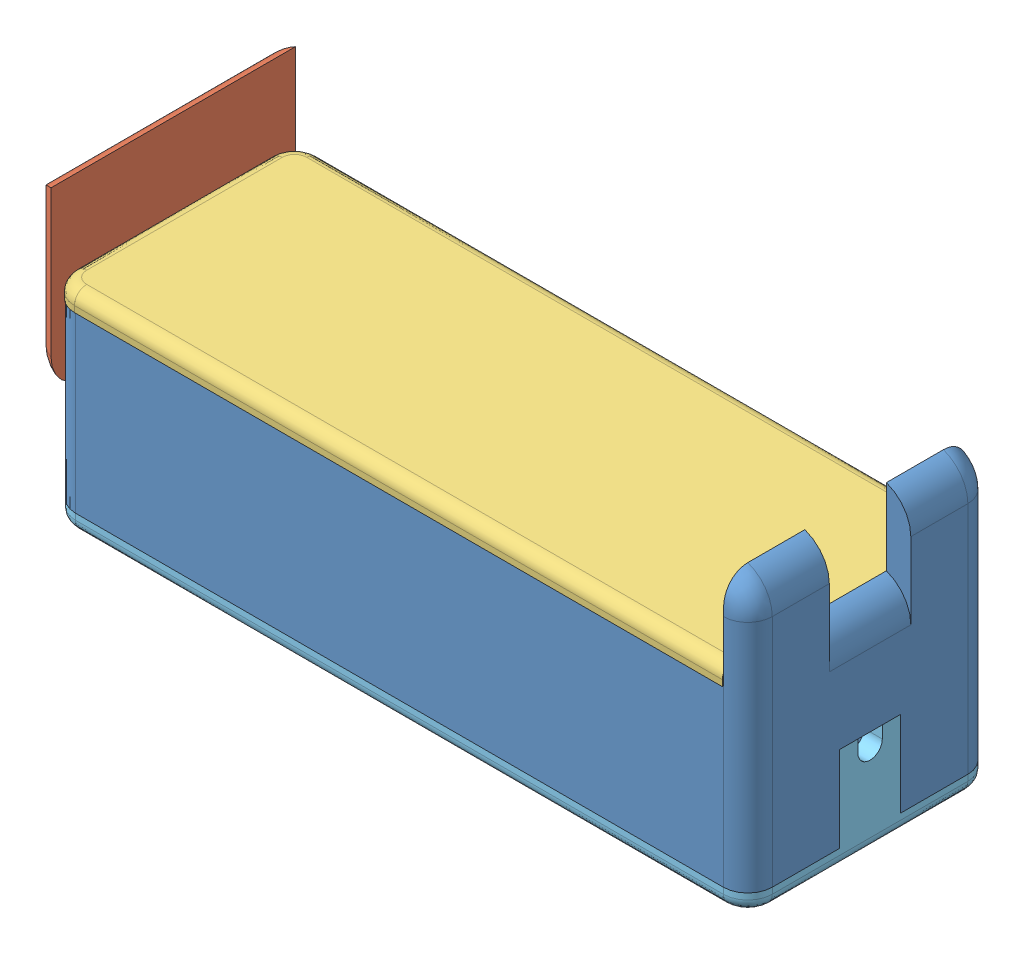
SolidWorks assembly Assem1, configuration Default. Lengths in mm.
Overall size (149.86 60.32 51.83).
7 component instances, 6 part files, 19 mates.
Components (placement in the parent):
- body-1: body [Default] at (48.1524 73.359 115.7305) size (144.78 56.51 51.83)
- slider-1: slider [Default] at (-26.7776 92.536 115.7305) x (0 0 -1) z (1 0 0) size (50.8 37.66 93.98)
- spring-cover-1: spring-cover [Default] at (48.1524 91.774 115.9424) size (139.7 3.81 50.8)
- spring-1: spring [Default] at (102.2544 86.3892 129.1216) x (0 -0.455793 -0.890086) z (-1 0 0) size (9.55 9.55 32.26)
- spring-2: spring [Default] at (69.9964 86.3892 101.602) x (0 0 -1) z (1 0 0) size (9.55 9.55 32.26)
- sensor-cover-1: sensor-cover [Default] at (50.6924 51.769 115.7305) size (144.78 21.59 50.8)
- lidar-1: lidar [Default] at (3.7024 67.945 115.9927) x (0 0 -1) z (-1 0 0) size (42 16.18 15.24)
Mates (geometry in assembly coordinates):
- Tangent1: tangent anti-aligned: cylinder of body-1 through (105.9374 102.1911 102.3955) axis (0 -1 0) radius 3.683; plane of spring-2 through (102.2544 86.3892 101.602) normal (1 0 0)
- Parallel1: parallel anti-aligned: plane of body-1 through (114.1924 91.774 115.7305) normal (-1 0 0); plane of spring-2 through (102.2544 86.3892 101.602) normal (1 0 0)
- Tangent2: tangent anti-aligned: plane of body-1 through (48.1524 81.614 115.7305) normal (0 1 0); cylinder of spring-2 through (102.2544 86.3892 101.602) axis (-1 0 0) radius 4.7752
- Tangent3: tangent anti-aligned: plane of body-1 through (48.1524 81.614 115.7305) normal (0 1 0); cylinder of spring-1 through (69.9964 86.3892 129.1216) axis (1 0 0) radius 4.7752
- Parallel2: parallel anti-aligned: plane of body-1 through (114.1924 91.774 115.7305) normal (-1 0 0); plane of spring-1 through (102.2544 86.3892 129.1216) normal (1 0 0)
- Tangent4: tangent anti-aligned: cylinder of body-1 through (105.9374 102.1911 129.0655) axis (0 -1 0) radius 3.683; plane of spring-1 through (102.2544 86.3892 129.1216) normal (1 0 0)
- Coincident4: coincident anti-aligned: plane of body-1 through (48.1524 91.774 115.7305) normal (0 1 0); plane of spring-cover-1 through (48.1524 91.774 115.9424) normal (0 -1 0)
- Coincident5: coincident anti-aligned: plane of body-1 through (118.0024 73.359 115.7305) normal (-1 0 0); plane of spring-cover-1 through (118.0024 95.584 141.3424) normal (1 0 0)
- Coincident6: coincident anti-aligned: plane of body-1 through (48.1524 81.614 115.7305) normal (0 1 0); plane of slider-1 through (54.5024 81.614 137.3205) normal (0 -1 0)
- Coincident7: coincident anti-aligned: plane of body-1 through (48.1524 91.774 137.3205) normal (0 0 -1); plane of slider-1 through (54.5024 91.774 137.3205) normal (0 0 1)
- LimitDistance1: limit distance = 0 mm anti-aligned: plane of slider-1 through (-21.6976 92.536 115.7305) normal (1 0 0); plane of body-1 through (-21.6976 81.614 141.1305) normal (-1 0 0)
- LimitDistance3: limit distance = 72.39 mm anti-aligned: plane of slider-1 through (54.5024 92.536 115.7305) normal (-1 0 0); plane of body-1 through (-17.8876 91.774 115.7305) normal (1 0 0)
- Coincident17: coincident anti-aligned: plane of body-1 through (48.1524 55.579 115.7305) normal (0 -1 0); plane of sensor-cover-1 through (50.6924 55.579 115.7305) normal (0 1 0)
- Parallel3: parallel anti-aligned: plane of body-1 through (48.1524 73.359 115.7305) normal (0 -1 0); plane of lidar-1 through (3.7024 67.945 115.9927) normal (0 1 0)
- Parallel4: parallel anti-aligned: plane of body-1 through (-17.8876 55.579 137.3205) normal (1 0 0); plane of lidar-1 through (-3.9176 56.769 99.4827) normal (-1 0 0)
- Coincident20: coincident anti-aligned: plane of body-1 through (-3.9176 35.8224 137.3205) normal (1 0 0); plane of lidar-1 through (-3.9176 56.769 99.4827) normal (-1 0 0)
- Coincident21: coincident aligned: plane of sensor-cover-1 through (50.6924 51.769 115.7305) normal (0 -1 0); plane of lidar-1 through (3.7024 51.769 120.9927) normal (0 -1 0)
- LimitDistance5: limit distance = 0 mm aligned: plane of sensor-cover-1 through (123.0824 55.579 141.1305) normal (1 0 0); plane of body-1 through (123.0824 73.359 115.7305) normal (1 0 0)
- Coincident25: coincident aligned: plane of body-1 through (-21.6976 81.614 90.3305) normal (0 0 -1); plane of sensor-cover-1 through (-21.6976 55.579 90.3305) normal (0 0 -1)
